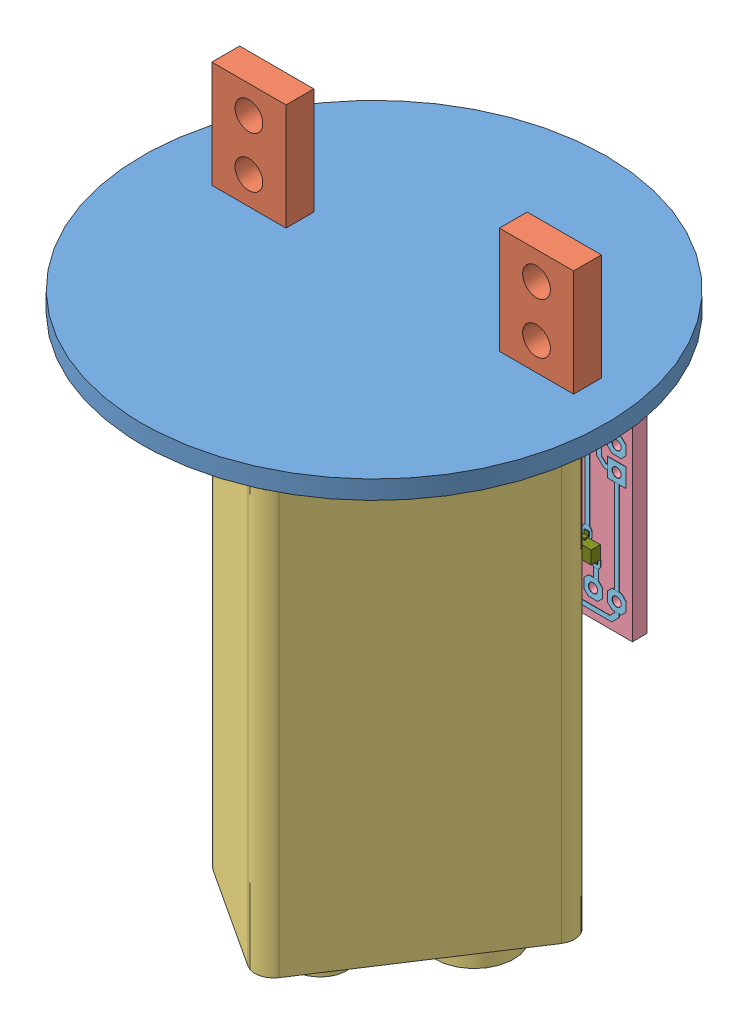
SolidWorks assembly Elektro, configuration Standard. Lengths in mm.
Overall size (74.46 63.5 55.28).
24 component instances, 22 part files, 8 mates.
Components (placement in the parent):
- E-Part-1: E-Part [Standard] at (0.3501 -2.1253 50) size (74.46 2 55.28)
- E-Befestigung-1: E-Befestigung [Standard] at (-10.1499 -0.1253 49) size (8 11.5 3)
- E-Befestigung-2: E-Befestigung [Standard] at (20.8501 -0.1253 49) size (8 11.5 3)
- 9V-1: 9V [Standard] at (-3.3779 -2.1253 64.2356) x (-0.837169 0 -0.546944) z (-0.546944 0 0.837169) size (17 50 26)
- Zeitschaltung-1: Zeitschaltung [Standard] at (0.1444 -17.1253 36.1566) size (30 30 12.43)
  - Zeitschaltung_Board-1: Zeitschaltung_Board [Standard] at origin size (30 30 1.6)
  - Zeitschaltung_PadsAndTracks-1: Zeitschaltung_PadsAndTracks [Standard] at origin size (28.67 28.55 1.67)
  - Zeitschaltung_K1-1: Zeitschaltung_K1 [Standard] at origin size (2.54 5.08 10.74) (hidden)
  - Zeitschaltung_K2-1: Zeitschaltung_K2 [Standard] at origin size (7.62 2.54 10.74) (hidden)
  - Zeitschaltung_K3-1: Zeitschaltung_K3 [Standard] at origin size (7.62 2.54 10.74) (hidden)
  - Zeitschaltung_K4-1: Zeitschaltung_K4 [Standard] at origin size (5.08 7.62 10.74)
  - Zeitschaltung_K6-1: Zeitschaltung_K6 [Standard] at origin size (2.54 5.08 10.74) (hidden)
  - Zeitschaltung_IC3-1: Zeitschaltung_IC3 [Standard] at origin size (8.8 8.8 1.61)
  - Zeitschaltung_D5-1: Zeitschaltung_D5 [Standard] at origin size (3.7 3 2.09)
  - Zeitschaltung_R1-1: Zeitschaltung_R1 [Standard] at origin size (3.2 1.6 0.61)
  - Zeitschaltung_R5-1: Zeitschaltung_R5 [Standard] at origin size (3.2 1.6 0.61)
  - Zeitschaltung_K5-1: Zeitschaltung_K5 [Standard] at origin size (17.78 2.54 12) (hidden)
  - Zeitschaltung_R4-1: Zeitschaltung_R4 [Standard] at origin size (3.2 1.6 0.61)
  - Zeitschaltung_X2-1: Zeitschaltung_X2 [Standard] at origin size (5 6.04 1.86)
  - Zeitschaltung_C2-1: Zeitschaltung_C2 [Standard] at origin size (3.2 1.6 0.61)
  - Zeitschaltung_R2-1: Zeitschaltung_R2 [Standard] at origin size (4.7 6.5 7)
  - Zeitschaltung_T1-1: Zeitschaltung_T1 [Standard] at origin size (10.42 6.5 2.38)
  - Zeitschaltung_K7-1: Zeitschaltung_K7 [Standard] at origin size (2.54 5.08 12) (hidden)
  - Zeitschaltung_T2-1: Zeitschaltung_T2 [Standard] at origin size (3 2.6 1.1)
Mates (geometry in assembly coordinates):
- Deckungsgleich5: coincident anti-aligned: plane of E-Part-1 through (0.3501 -0.1253 50) normal (0 1 0); plane of E-Befestigung-1 through (-10.1499 -0.1253 49) normal (0 -1 0)
- Deckungsgleich6: coincident anti-aligned: plane of E-Part-1 through (0.3501 -0.1253 50) normal (0 1 0); plane of E-Befestigung-2 through (20.8501 -0.1253 49) normal (0 -1 0)
- Abstand2: distance = 10.5 mm: line of E-Befestigung-1 through (-10.1499 -0.1253 49) axis (0 0 -1); line of E-Part-1 through (0.3501 -0.1253 22.8782) axis (0 0 1)
- Abstand3: distance = 12.5 mm: line of E-Befestigung-2 through (12.8501 -0.1253 46) axis (0 0 1); line of E-Part-1 through (0.3501 -0.1253 22.8782) axis (0 0 1)
- Abstand6: distance = 4 mm: line of E-Befestigung-2 through (20.8501 -0.1253 46) axis (-1 0 0); line of E-Part-1 through (36.8365 -0.1253 50) axis (-1 0 0)
- Abstand7: distance = 4 mm: line of E-Befestigung-1 through (-10.1499 -0.1253 46) axis (-1 0 0); line of E-Part-1 through (36.8365 -0.1253 50) axis (-1 0 0)
- Deckungsgleich14: coincident anti-aligned: plane of E-Part-1 through (0.3501 -2.1253 50) normal (0 -1 0); plane of 9V-1 through (-3.3779 -2.1253 64.2356) normal (0 1 0)
- Deckungsgleich15: coincident anti-aligned: plane of E-Part-1 through (0.3501 -2.1253 50) normal (0 -1 0); plane of Zeitschaltung-1/Zeitschaltung_Board-1 through (15.1444 -2.1253 35.3566) normal (0 1 0)
